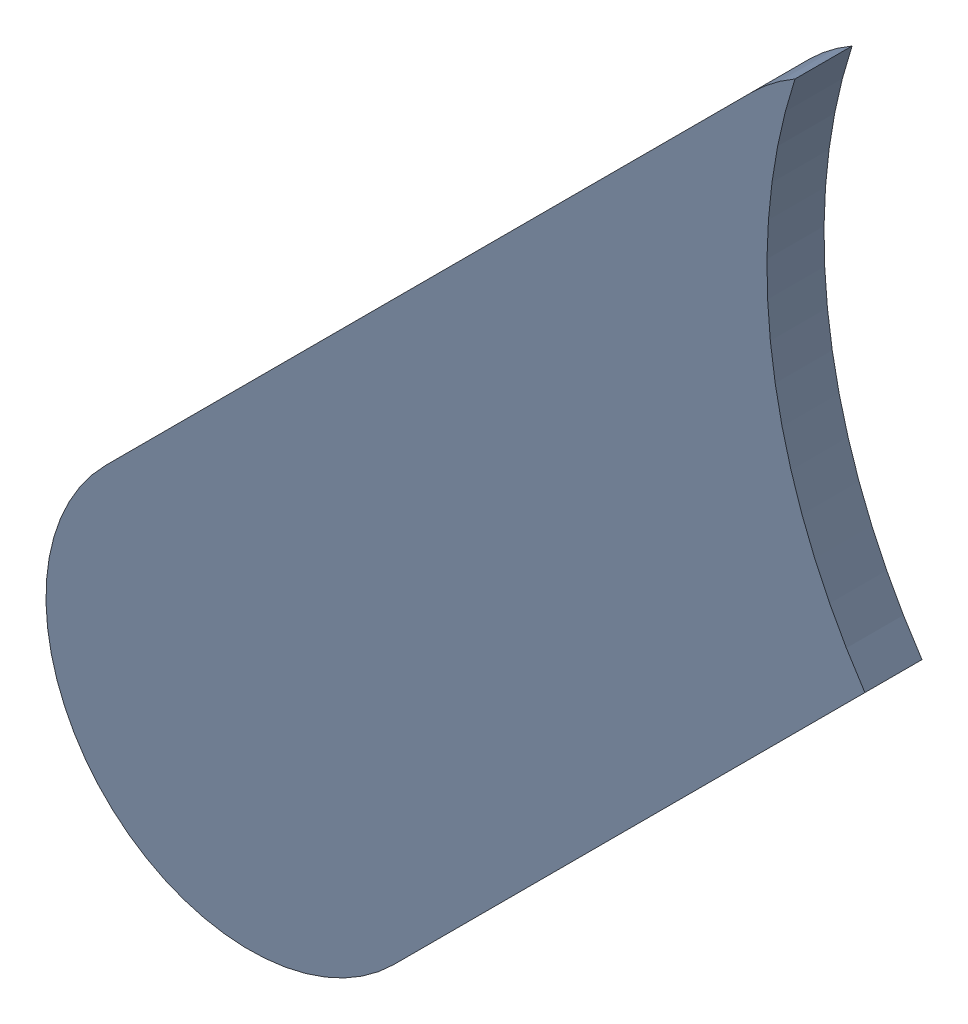
SolidWorks assembly Track (23.822mm,58.097mm)(24.225mm,58.5mm) on Top Layer, configuration Predeterminado. Lengths in mm.
Overall size (0.51 0.64 0.04).
2 component instances, 1 part files, 0 mates.
Components (placement in the parent):
- Track (23.822mm,58.097mm)(24.225mm,58.5mm) on Top Layer-1-1: Track (23.822mm,58.097mm)(24.225mm,58.5mm) on Top Layer-1 [Predeterminado] at (-68.317 -44.187 -0.0457) size (0.51 0.64 0.04)
  - Track (23.822mm,58.097mm)(24.225mm,58.5mm) on Top Layer-Part-1-1: Track (23.822mm,58.097mm)(24.225mm,58.5mm) on Top Layer-Part-1 [Predeterminado] at origin size (0.51 0.64 0.04)
